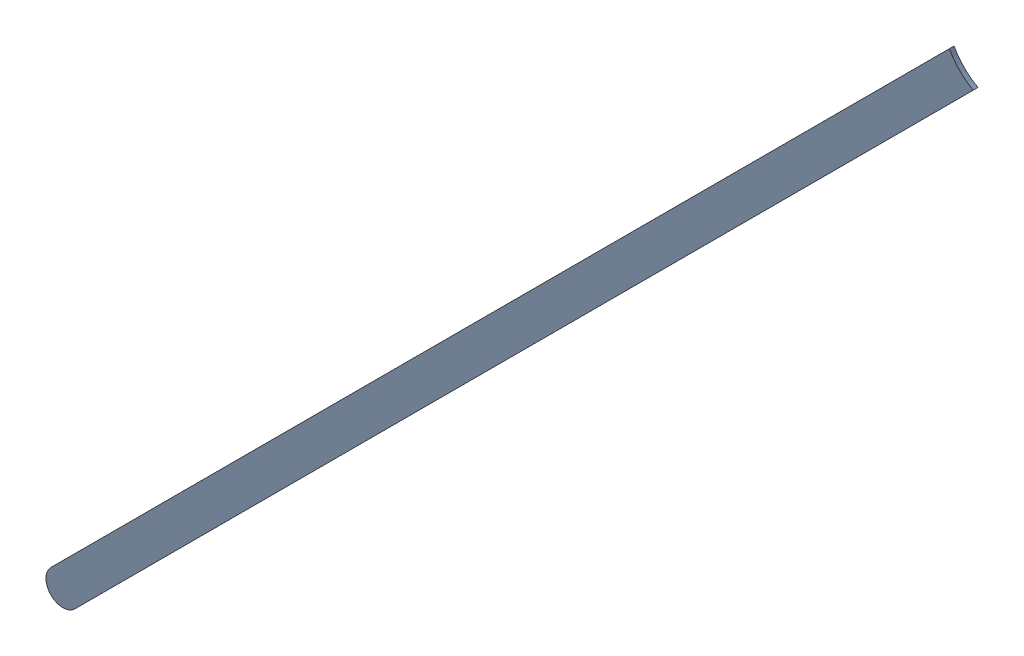
SolidWorks assembly Track (8.493mm,36.353mm)(15.54mm,43.4mm) on Bottom Layer, configuration Predeterminado. Lengths in mm.
Overall size (6.96 6.96 0.04).
2 component instances, 1 part files, 0 mates.
Components (placement in the parent):
- Track (8.493mm,36.353mm)(15.54mm,43.4mm) on Bottom Layer-1-1: Track (8.493mm,36.353mm)(15.54mm,43.4mm) on Bottom Layer-1 [Predeterminado] at (-68.317 -44.187 -0.4013) size (6.96 6.96 0.04)
  - Track (8.493mm,36.353mm)(15.54mm,43.4mm) on Bottom Layer-Part-1-1: Track (8.493mm,36.353mm)(15.54mm,43.4mm) on Bottom Layer-Part-1 [Predeterminado] at origin size (6.96 6.96 0.04)
